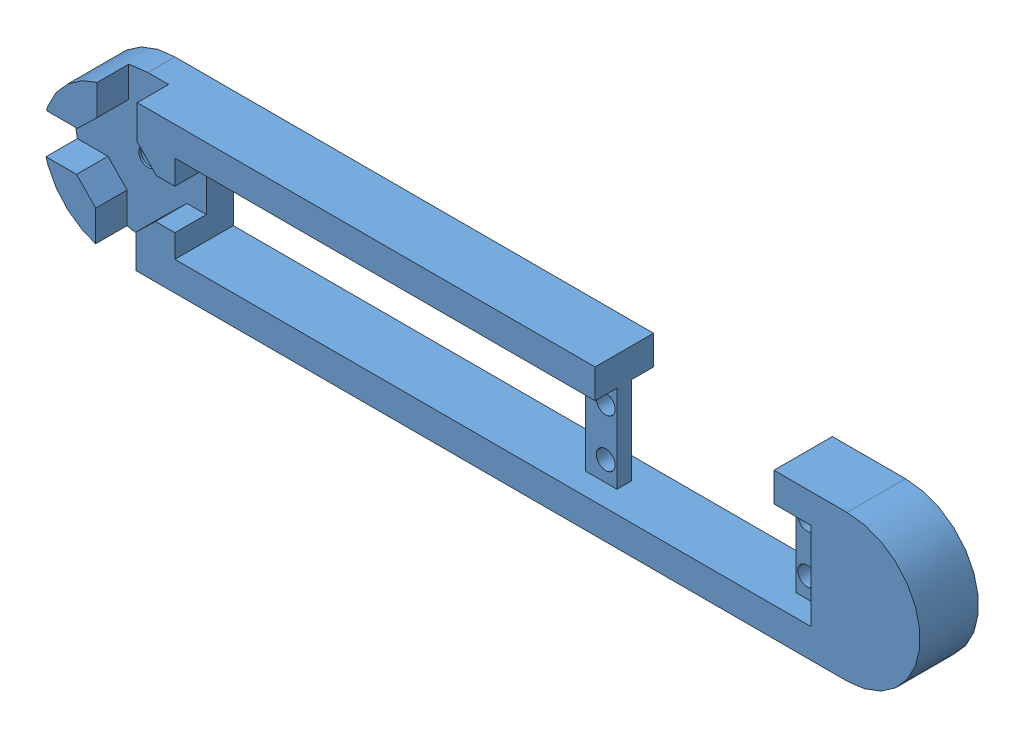
SolidWorks assembly testBras, configuration Défaut. Lengths in mm.
Overall size (120 20 8).
2 component instances, 2 part files, 3 mates.
Components (placement in the parent):
- bras-1: bras [Défaut] at (-74.5383 -8.1052 -2) size (120 20 8)
- servo-1: servo [Défaut] at (-8.5231 -3.9052 -3.5325) x (0 0 1) z (0 1 0) (suppressed, hidden)
Mates (geometry in assembly coordinates):
- Coïncidente1: coincident anti-aligned: plane of bras-1 through (-9.0231 7.8948 1) normal (0 0 -1); plane of servo-1 through (19.5439 -3.9052 1) normal (0 0 1)
- Distance2: distance = 0.5 mm aligned: plane of servo-1 through (-12.8411 7.7788 -2.429) normal (-1 0 0); plane of bras-1 through (-13.3411 499991.8948 -2) normal (-1 0 0)
- Distance3: distance = 0.2 mm anti-aligned: plane of servo-1 through (15.2259 -3.9052 -3.5325) normal (0 -1 0); plane of bras-1 through (-66.5383 -4.1052 -2) normal (0 1 0)
